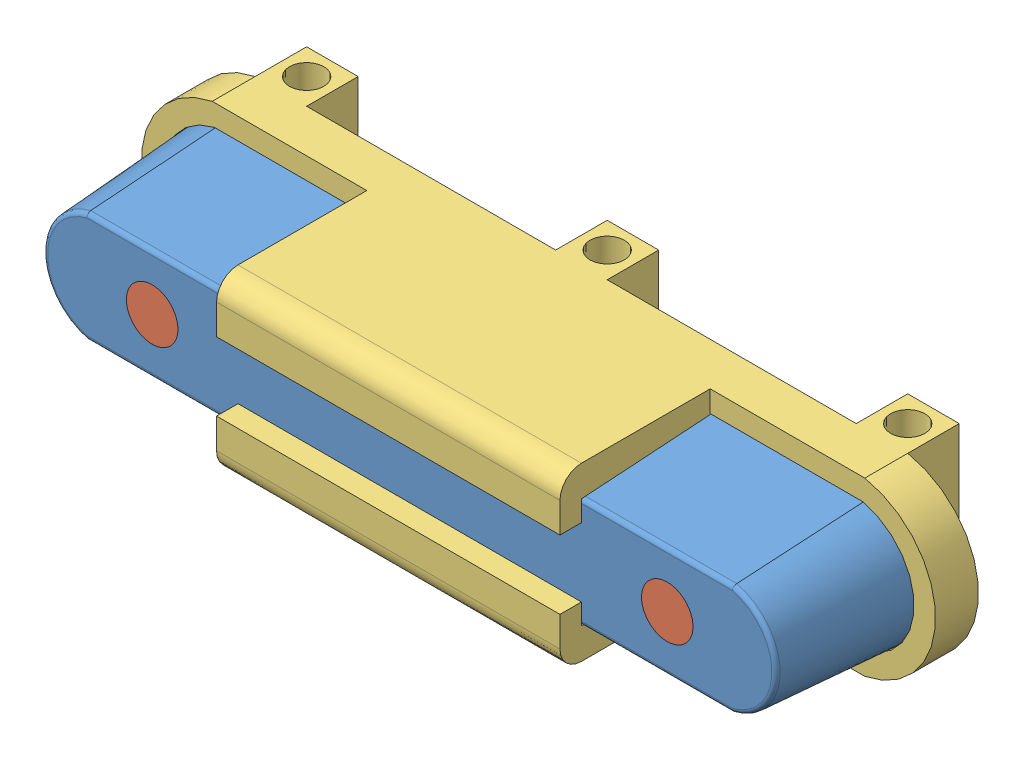
SolidWorks assembly StereoLab-ZED, configuration Default. Lengths in mm.
Overall size (185 40 57).
4 component instances, 3 part files, 5 mates.
Components (placement in the parent):
- ZED-Body-1: ZED-Body [Default] at (47.6321 101.7598 136.5731) size (175 30 33)
- ZED-Glass-1: ZED-Glass [Default] at (-12.3679 101.7598 167.5731) size (12 12 2)
- ZED-Glass-2: ZED-Glass [Default] at (107.6321 101.7598 167.5731) size (12 12 2)
- ZedHolder-1: ZedHolder [Default] at (47.6321 101.7598 129.5731) size (185 40 57)
Mates (geometry in assembly coordinates):
- Coincidente2: coincident aligned: circle of ZED-Body-1; circle of ZED-Glass-1
- Coincidente3: coincident aligned: circle of ZED-Body-1; circle of ZED-Glass-2
- Coincidente4: coincident aligned: line of ZED-Body-1 through (123.1321 116.7598 136.5731) axis (-1 0 0); line of ZedHolder-1 through (123.1321 116.7598 136.5731) axis (-1 0 0)
- Coincidente5: coincident aligned: line of ZED-Body-1 through (-27.8679 86.7598 136.5731) axis (1 0 0); line of ZedHolder-1 through (-27.8679 86.7598 136.5731) axis (1 0 0)
- Coincidente6: coincident aligned: circle of ZED-Body-1; circle of ZedHolder-1
